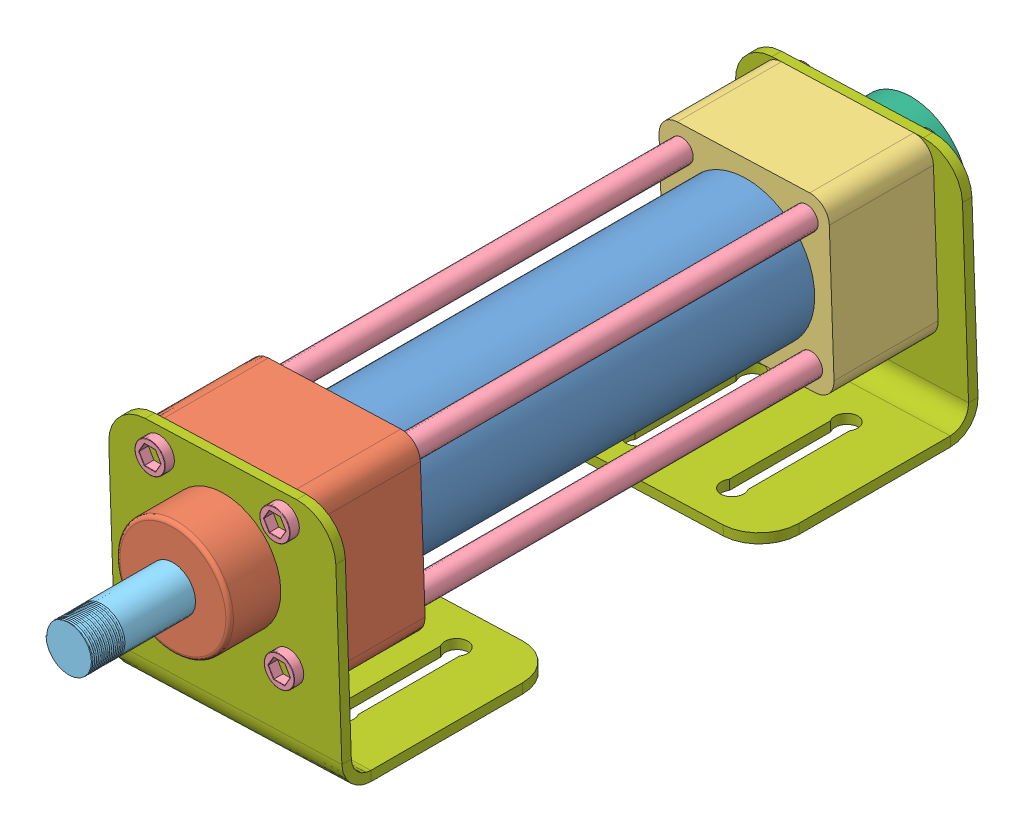
SolidWorks assembly pnumetic cylinder, configuration Default. Lengths in mm.
Overall size (62.17 64.58 222.63).
11 component instances, 7 part files, 25 mates.
Components (placement in the parent):
- cylinder tube-1: cylinder tube [Default] at (103.244 123.1984 58.4037) size (36 36 110)
- cylinder part one-1: cylinder part one [Default] at (126.5261 101.5086 194.9037) x (0.035384 -0.999374 0) z (0 0 -1) size (45 45 43.5)
- cylinder part two1-1: cylinder part two1 [Default] at (124.9338 146.4804 31.9037) x (-0.035384 0.999374 0) z (0 0 1) size (45 45 27.5)
- cylinder bolt-1: cylinder bolt [Default] at (87.3382 106.1249 113.4037) x (1 0 0) z (0 1 0) size (8 173 8)
- cylinder bolt-2: cylinder bolt [Default] at (120.3176 107.2925 113.4037) x (1 0 0) z (0 1 0) size (8 173 8)
- cylinder bolt-3: cylinder bolt [Default] at (119.1499 140.2719 113.4037) x (1 0 0) z (0 1 0) size (8 173 8)
- cylinder bolt-4: cylinder bolt [Default] at (86.1705 139.1042 113.4037) x (1 0 0) z (0 1 0) size (8 173 8)
- piston-1: piston [Default] at (103.244 123.1984 58.4037) x (0.70948 -0.704726 0) z (0 0 1) size (32 32 180.13)
- extra part-1: extra part [Default] at (103.244 123.1984 15.9037) size (30 30 16)
- fixation-2: fixation [Default] at (134.7291 81.7865 139.9037) x (-0.999374 -0.035384 0) z (-0.035384 0.999374 0) size (60 57.5 62.5)
- fixation-3: fixation [Default] at (74.7667 79.6635 86.9037) x (0.999374 0.035384 0) z (-0.035384 0.999374 0) size (60 57.5 62.5)
Mates (geometry in assembly coordinates):
- Coincident1: coincident anti-aligned: plane of cylinder tube-1 through (103.244 123.1984 168.4037) normal (0 0 1); plane of cylinder part one-1 through (103.244 123.1984 168.4037) normal (0 0 -1)
- Coincident2: coincident anti-aligned: circle of cylinder tube-1; circle of cylinder part one-1
- Coincident3: coincident anti-aligned: plane of cylinder tube-1 through (103.244 123.1984 58.4037) normal (0 0 -1); plane of cylinder part two1-1 through (103.244 123.1984 58.4037) normal (0 0 1)
- Coincident4: coincident aligned: circle of cylinder tube-1; circle of cylinder part two1-1
- Coincident5: coincident aligned: plane of cylinder part one-1 through (84.9589 145.0651 167.4037) normal (-0.035384 0.999374 0); plane of cylinder part two1-1 through (84.9589 145.0651 59.4037) normal (-0.035384 0.999374 0)
- Concentric2: concentric anti-aligned: cylinder of cylinder part two1-1 through (87.3382 106.1249 59.4037) axis (0 0 -1) radius 3; cylinder of cylinder bolt-1 through (87.3382 106.1249 31.9037) axis (0 0 1) radius 3
- Coincident7: coincident anti-aligned: plane of cylinder part two1-1 through (86.3742 105.0901 31.9037) normal (0 0 -1); plane of cylinder bolt-1 through (87.3382 106.1249 31.9037) normal (0 0 1)
- Coincident8: coincident anti-aligned: circle of cylinder part one-1; cylinder of cylinder bolt-2 through (120.3176 107.2925 31.9037) axis (0 0 1) radius 3
- Coincident9: coincident anti-aligned: plane of cylinder part one-1 through (85.1358 140.0682 194.9037) normal (0 0 1); plane of cylinder bolt-2 through (120.3176 107.2925 194.9037) normal (0 0 -1)
- Concentric3: concentric aligned: cylinder of cylinder part one-1 through (86.1705 139.1042 167.4037) axis (0 0 1) radius 3; cylinder of cylinder bolt-4 through (86.1705 139.1042 31.9037) axis (0 0 1) radius 3
- Coincident10: coincident anti-aligned: plane of cylinder part one-1 through (85.1358 140.0682 194.9037) normal (0 0 1); plane of cylinder bolt-4 through (86.1705 139.1042 194.9037) normal (0 0 -1)
- Concentric4: concentric aligned: cylinder of cylinder part one-1 through (119.1499 140.2719 167.4037) axis (0 0 1) radius 3; cylinder of cylinder bolt-3 through (119.1499 140.2719 31.9037) axis (0 0 1) radius 3
- Coincident11: coincident anti-aligned: plane of cylinder part one-1 through (85.1358 140.0682 194.9037) normal (0 0 1); plane of cylinder bolt-3 through (119.1499 140.2719 194.9037) normal (0 0 -1)
- Concentric5: concentric aligned: cylinder of cylinder tube-1 through (103.244 123.1984 168.4037) axis (0 0 -1) radius 16; cylinder of piston-1 through (103.244 123.1984 68.4037) axis (0 0 -1) radius 16
- LimitDistance1: limit distance = 0 mm anti-aligned: plane of cylinder part two1-1 through (103.244 123.1984 58.4037) normal (0 0 1); plane of piston-1 through (103.244 123.1984 58.4037) normal (0 0 -1)
- Concentric9: concentric anti-aligned: cylinder of piston-1 through (103.244 123.1984 238.4037) axis (0 0 -1) radius 6; cylinder of nut-2 through (103.244 123.1984 254.4183) axis (0 0 1) radius 5
- Distance2: distance = 5 mm aligned: plane of nut-2 through (103.244 123.1984 259.4183) normal (0 0 1); plane of piston-1 through (103.244 123.1984 238.4037) normal (0 0 1)
- Coincident12: coincident anti-aligned: plane of cylinder part two1-1 through (86.3742 105.0901 31.9037) normal (0 0 -1); plane of extra part-1 through (103.244 123.1984 31.9037) normal (0 0 1)
- Concentric10: concentric aligned: cylinder of piston-1 through (103.244 123.1984 68.4037) axis (0 0 -1) radius 16; cylinder of extra part-1 through (103.244 123.1984 31.9037) axis (0 0 -1) radius 15
- Concentric11: concentric aligned: cylinder of extra part-1 through (103.244 123.1984 31.9037) axis (0 0 -1) radius 15; cylinder of fixation-3 through (103.244 123.1984 31.9037) axis (0 0 -1) radius 15
- Parallel1: parallel anti-aligned: line of cylinder part two1-1 through (126.3492 106.5055 31.9037) axis (-0.035384 0.999374 0); line of fixation-3 through (132.783 136.7521 31.9037) axis (0.035384 -0.999374 0)
- Coincident14: coincident anti-aligned: plane of cylinder part two1-1 through (86.3742 105.0901 31.9037) normal (0 0 -1); plane of fixation-3 through (72.4667 144.6228 31.9037) normal (0 0 1)
- Concentric12: concentric anti-aligned: cylinder of cylinder part one-1 through (103.244 123.1984 210.9037) axis (0 0 -1) radius 15; cylinder of fixation-2 through (103.244 123.1984 194.9037) axis (0 0 1) radius 15
- Parallel2: parallel aligned: line of cylinder part one-1 through (125.1107 141.4836 194.9037) axis (0.035384 -0.999374 0); line of fixation-2 through (132.783 136.7521 194.9037) axis (0.035384 -0.999374 0)
- Coincident16: coincident anti-aligned: plane of cylinder part one-1 through (85.1358 140.0682 194.9037) normal (0 0 1); plane of fixation-2 through (132.4291 146.7458 194.9037) normal (0 0 -1)
